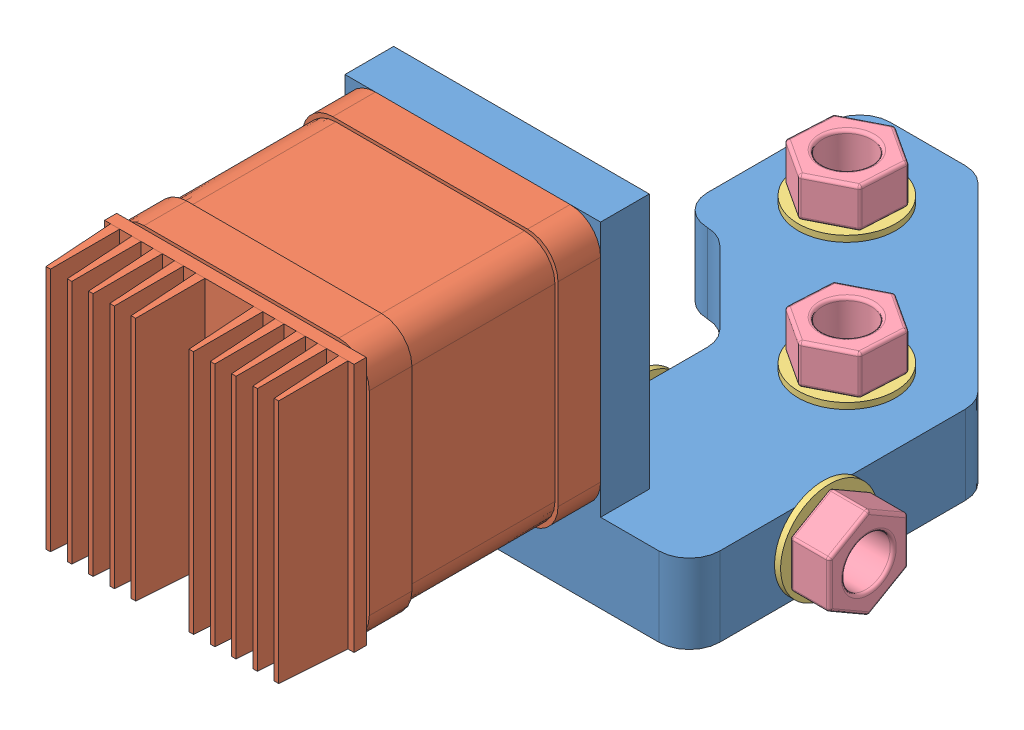
SolidWorks assembly Motor Ass + Middle Corner, configuration Default. Lengths in mm.
Overall size (64.08 62.5 131).
16 component instances, 5 part files, 14 mates.
Components (placement in the parent):
- Corner (Middle - Motor)-1: Corner (Middle - Motor) [Default] at (-8.1523 -19.5688 -12.1633) size (56.58 55 80)
- Motor with Coupler-1: Motor with Coupler [Default] at (23.9359 0.0529 67.0139) x (1 0 0) z (0 1 0) size (42 63 44.5)
  - NEMA17-1: NEMA17 [Default] at (-37.3382 -8.8228 14.3783) size (42 63 44.5)
  - GT2-1: GT2 [Default] at (-37.3382 34.1772 14.3783) size (14 8.5 14)
- M8 Washer 16mm-1: M8 Washer 16mm [Default] at (6.8477 -20.5688 -3.3765) size (16 1 16)
- M8 Washer 16mm-2: M8 Washer 16mm [Default] at (23.1788 -13.0688 15.8367) x (0 1 0) z (0 0 1) size (16 1 16)
- M8 Washer 16mm-3: M8 Washer 16mm [Default] at (-16.9391 -20.5688 -27.1633) size (16 1 16)
- M8 Washer 16mm-4: M8 Washer 16mm [Default] at (6.8477 -6.5688 -3.3765) size (16 1 16)
- M8 Washer 16mm-5: M8 Washer 16mm [Default] at (-7.8212 -13.0688 15.8367) x (0 1 0) z (0 0 1) size (16 1 16)
- M8 Washer 16mm-6: M8 Washer 16mm [Default] at (-16.9391 -6.5688 -27.1633) size (16 1 16)
- M8 Nut-1: M8 Nut [Default] at (6.8477 0.9312 -3.3765) x (-0.837169 0 -0.546944) z (-0.546944 0 0.837169) size (14.85 6.5 12.99)
- M8 Nut-2: M8 Nut [Default] at (29.6788 -13.0688 15.8367) x (0 1 0) z (0 0 1) size (14.85 6.5 12.99)
- M8 Nut-3: M8 Nut [Default] at (-15.3212 -13.0688 15.8367) x (0 -1 0) z (0 0 1) size (14.85 6.5 12.99)
- M8 Nut-4: M8 Nut [Default] at (6.8477 -27.0688 -3.3765) size (14.85 6.5 12.99)
- M8 Nut-5: M8 Nut [Default] at (-16.9391 -27.0688 -27.1633) size (14.85 6.5 12.99)
- M8 Nut-6: M8 Nut [Default] at (-16.9391 0.9312 -27.1633) x (-0.837169 0 -0.546944) z (-0.546944 0 0.837169) size (14.85 6.5 12.99)
Mates (geometry in assembly coordinates):
- Coincident1: coincident anti-aligned: circle of Corner (Middle - Motor)-1; circle of Motor with Coupler-1/NEMA17-1
- Coincident3: coincident anti-aligned: circle of Corner (Middle - Motor)-1; circle of Motor with Coupler-1/NEMA17-1
- Coincident5: coincident aligned: circle of M8 Washer 16mm-2; circle of Corner (Middle - Motor)-1
- Coincident6: coincident aligned: circle of Corner (Middle - Motor)-1; circle of M8 Washer 16mm-4
- Coincident7: coincident aligned: circle of Corner (Middle - Motor)-1; circle of M8 Washer 16mm-6
- Coincident8: coincident aligned: circle of Corner (Middle - Motor)-1; circle of M8 Washer 16mm-1
- Coincident9: coincident aligned: circle of Corner (Middle - Motor)-1; circle of M8 Washer 16mm-3
- Coincident10: coincident aligned: circle of M8 Washer 16mm-5; circle of Corner (Middle - Motor)-1
- Coincident11: coincident aligned: circle of M8 Nut-1; circle of M8 Washer 16mm-4
- Coincident12: coincident anti-aligned: circle of M8 Washer 16mm-2; circle of M8 Nut-2
- Coincident13: coincident aligned: circle of M8 Nut-6; circle of M8 Washer 16mm-6
- Coincident14: coincident anti-aligned: circle of M8 Nut-4; circle of M8 Washer 16mm-1
- Coincident15: coincident anti-aligned: circle of M8 Washer 16mm-3; circle of M8 Nut-5
- Coincident16: coincident aligned: circle of M8 Nut-3; circle of M8 Washer 16mm-5
